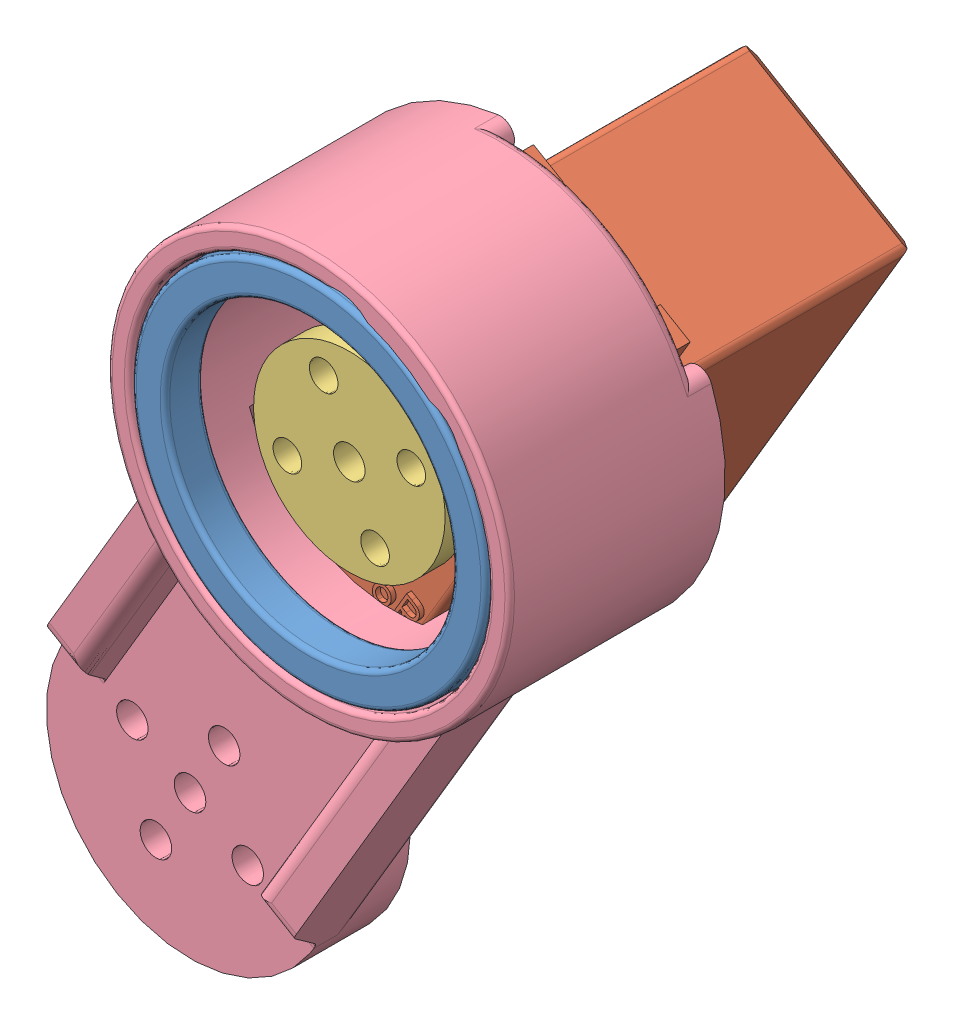
SolidWorks assembly 大腿总成, configuration 默认. Lengths in mm.
Overall size (85.86 105.42 50.13).
4 component instances, 4 part files, 7 mates.
Components (placement in the parent):
- 6706一30x37x4轴承-1: 6706一30x37x4轴承 [默认] at (2.2614 -2.2522 35) size (37 37 4)
- MG996R-1: MG996R [默认] at (-4.4474 -33.139 -10.9) x (0.509094 0.860711 0) z (0.860711 -0.509094 0) size (54 43.2 19.9)
- 舵盘-1: 舵盘 [默认] at (2.3101 -2.281 32.3) x (-0.923728 -0.383049 0) z (0 0 -1) size (20 20 4.5)
- 舵机固定件_大腿-1: 舵机固定件_大腿 [默认] at (16.8989 1.8701 20) x (-0.509094 -0.860711 0) z (0 0 -1) size (97.64 42 27.23)
Mates (geometry in assembly coordinates):
- 同心2: concentric aligned: circle of MG996R-1; circle of 舵机固定件_大腿-1
- 重合1: coincident anti-aligned: plane of MG996R-1 through (-4.4474 -33.139 18) normal (0 0 1); plane of 舵机固定件_大腿-1 through (16.8989 1.8701 18) normal (0 0 -1)
- 重合2: coincident anti-aligned: plane of MG996R-1 through (2.3101 -2.281 32.3) normal (0 0 1); plane of 舵盘-1 through (2.3101 -2.281 32.3) normal (0 0 -1)
- 同心3: concentric aligned: circle of MG996R-1; circle of 舵盘-1
- 重合3: coincident anti-aligned: plane of 6706一30x37x4轴承-1 through (2.2614 -2.2522 35) normal (0 0 -1); plane of 舵机固定件_大腿-1 through (16.8989 1.8701 35) normal (0 0 1)
- 同心4: concentric anti-aligned: circle of 6706一30x37x4轴承-1; circle of 舵机固定件_大腿-1
- 同心7: concentric aligned: circle of MG996R-1; circle of 舵机固定件_大腿-1
